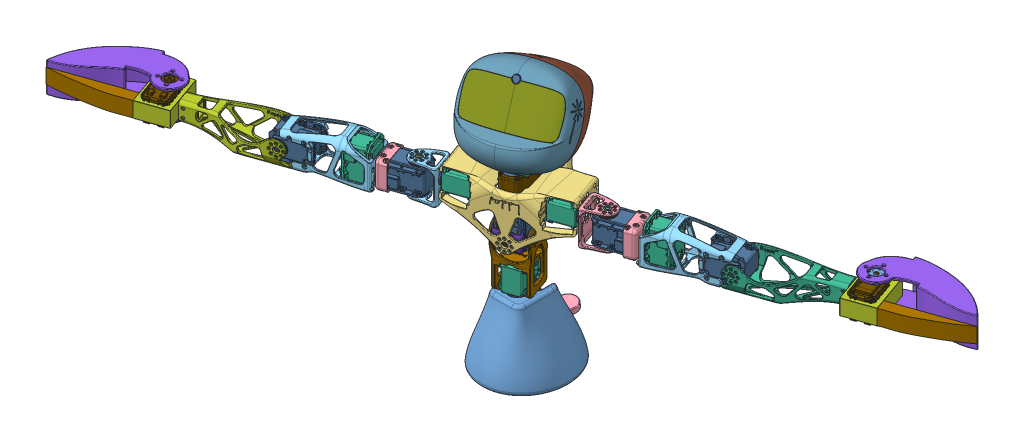
SolidWorks assembly table_support_w_suction_pad, configuration Default. Lengths in mm.
Overall size (1060.3 397.23 515.69).
149 component instances, 45 part files, 8 mates.
Components (placement in the parent):
- support_for_table-1: support_for_table [Défaut] at (0 97 0) size (172.24 95.75 137.34)
- 100LWBN-1: 100LWBN [Default] at (0 0 -15) x (0 0 -1) z (1 0 0) size (122.12 52 100)
  - 100LWBN_suction_pad-1: 100LWBN_suction_pad [Default] at origin size (100 52 100)
  - 100LWBN_shaft-1: 100LWBN_shaft [Default] at (0 35.0737 0) size (7 20 7)
  - 100LWBN_handle-1: 100LWBN_handle [Default] at (0 35.0737 0) x (-0.997983 -0.063481 0) z (0 0 -1) size (75.98 20.58 26)
- Poppy_Humanoid_Torso_Gripper-1: Poppy_Humanoid_Torso_Gripper [Default] at (-5.6475 -20.9875 -16.0345) x (0.943207 0 -0.332206) z (0.332206 0 0.943207) size (1063.51 305.58 172.17)
  - spine-1: spine [Default] at (0 138.4875 17) size (49.29 92.85 54.86)
    - MX-28(T)-2-1: MX-28(T)-2 [Default] x (1 0 0) z (0 -1 0) size (35.6 54.13 45.1)
      - WB_M2.5x8-1: WB_M2.5x8 [Default] at (0 0 25.85) x (0 0 -1) z (-0.991137 0.132843 0) size (10.5 4.5 4.5)
      - dynamixel_x28series(Défaut)-1: dynamixel_x28series(Défaut) [Default] at origin size (35.6 50.71 41.85)
      - trust_washer(Défaut)-1: trust_washer(Défaut) [Default] at (0 0 18.6) x (-0.666375 -0.745617 0) z (0.745617 -0.666375 0) size (22 0.85 22)
      - HN07-N101(Défaut)-1: HN07-N101(Défaut) [Default] at (0 0 18.5) x (1 0 0) z (0 -1 0) size (22 5.85 22)
    - spine-1: spine [Default] at (0 15 0.8) x (-1 0 0) z (0 0 -1) size (49.29 83.95 45.1)
  - double_rotation(full_MX28)-1: double_rotation(full_MX28) [Default] at (0 192.4875 19.8) size (48.5 54.13 85.1)
    - MX-28(U)-6-1: MX-28(U)-6 [Default] x (0 0 1) z (1 0 0) size (35.6 54.13 48.5)
      - dynamixel_x28series(U)-1: dynamixel_x28series(U) [Default] at origin size (35.6 50.71 41.85)
      - trust_washer(U)-1: trust_washer(U) [Default] at (0 0 18.6) x (-0.666375 -0.745617 0) z (0.745617 -0.666375 0) size (22 0.85 22)
      - HN07-N101(U)-1: HN07-N101(U) [Default] at (0 0 18.5) x (1 0 0) z (0 -1 0) size (22 5.85 22)
      - WB_M2.5x8-1: WB_M2.5x8 [Default] at (0 0 25.85) x (0 0 -1) z (-0.991137 0.132843 0) size (10.5 4.5 4.5)
      - WB_M2.5x8-2: WB_M2.5x8 [Default] at (0 0 -22.65) x (0 0 1) z (-0.936501 0.350665 0) size (10.5 4.5 4.5)
      - RX28-CAP-1: RX28-CAP [Default] at (0 0 -20.35) x (-0.995735 -0.092256 0) z (0 0 -1) size (7.2 7.2 1.8)
      - MF106ZZ-1: MF106ZZ [Default] at (0 0 -20.35) x (0.888333 -0.4592 0) z (-0.4592 -0.888333 0) size (11.2 3 11.2)
      - HN07-i101-1: HN07-i101 [Default] at (0 0 -20.5) x (1 0 0) z (0 1 0) size (22 3.05 22)
    - MX-28(T)-3-1: MX-28(T)-3 [Default] at (0 0 -37) x (1 0 0) z (0 0 -1) size (35.6 54.13 45.1)
      - WB_M2.5x8-1: WB_M2.5x8 [Default] at (0 0 25.85) x (0 0 -1) z (-0.991137 0.132843 0) size (10.5 4.5 4.5)
      - dynamixel_x28series(Défaut)-1: dynamixel_x28series(Défaut) [Default] at origin size (35.6 50.71 41.85)
      - trust_washer(Défaut)-1: trust_washer(Défaut) [Default] at (0 0 18.6) x (-0.666375 -0.745617 0) z (0.745617 -0.666375 0) size (22 0.85 22)
      - HN07-N101(Défaut)-1: HN07-N101(Défaut) [Default] at (0 0 18.5) x (1 0 0) z (0 -1 0) size (22 5.85 22)
    - i101_Set(FR07)-1: i101_Set(FR07) [Default] at (0 0 21.6) x (-0.798096 0.60253 0) z (0 0 1) size (22 22 3.8)
      - RX28-CAP-1: RX28-CAP [Default] at (0 0 -0.15) size (7.2 7.2 1.8)
      - MF106ZZ-1: MF106ZZ [Default] at (0 0 -0.15) x (-0.837169 0.546944 0) z (-0.546944 -0.837169 0) size (11.2 3 11.2)
      - HN07-i101-1: HN07-i101 [Default] x (1 0 0) z (0 -1 0) size (22 3.05 22)
    - double_rotation_link(double_MX28)-1: double_rotation_link(double_MX28) [Default] at (0 -0.5 0) size (7.4 26.51 14.1)
    - double_rotation_link(double_MX28)-2: double_rotation_link(double_MX28) [Default] at (0 8.5 0) x (-1 0 0) z (0 0 1) size (7.4 26.51 14.1)
    - i101-Set_to_MX_link(MX28_compatible)-1: i101-Set_to_MX_link(MX28_compatible) [Default] x (0 0 -1) z (1 0 0) size (8.29 28.53 35.81)
  - chest-1: chest [Default] at (7.2825 216.5654 -159.6611) size (167.7 95.79 102.98)
    - AX-12_18A-1: AX-12_18A [Default] at (-7.2825 38.9221 184.4611) x (-1 0 0) z (0 1 0) size (32 50.04 40.32)
      - dynamixel_AXseries-1: dynamixel_AXseries [Default] at origin size (32 50.04 38.37)
      - AX12_horn-1: AX12_horn [Default] at (0 0 19.1) x (0 1 0) z (0 0 1) size (22 22 6.7)
      - BHS_M2_6X8-1: BHS_M2_6X8 [Default] at (0 0 19.55) x (0.628847 -0.777529 0) z (-0.777529 -0.628847 0) size (5.5 9.6 5.5)
    - MX-28(T)-4-1: MX-28(T)-4 [Default] at (-65.2825 25.9221 183.4611) x (0 -1 0) z (-1 0 0) size (35.6 54.13 45.1)
      - WB_M2.5x8-1: WB_M2.5x8 [Default] at (0 0 25.85) x (0 0 -1) z (-0.991137 0.132843 0) size (10.5 4.5 4.5)
      - dynamixel_x28series(Défaut)-1: dynamixel_x28series(Défaut) [Default] at origin size (35.6 50.71 41.85)
      - trust_washer(Défaut)-1: trust_washer(Défaut) [Default] at (0 0 18.6) x (-0.666375 -0.745617 0) z (0.745617 -0.666375 0) size (22 0.85 22)
      - HN07-N101(Défaut)-1: HN07-N101(Défaut) [Default] at (0 0 18.5) x (1 0 0) z (0 -1 0) size (22 5.85 22)
    - MX-28(T)-5-1: MX-28(T)-5 [Default] at (50.7175 25.9221 183.4611) x (0 1 0) z (1 0 0) size (35.6 54.13 45.1)
      - WB_M2.5x8-1: WB_M2.5x8 [Default] at (0 0 25.85) x (0 0 -1) z (-0.991137 0.132843 0) size (10.5 4.5 4.5)
      - dynamixel_x28series(Défaut)-1: dynamixel_x28series(Défaut) [Default] at origin size (35.6 50.71 41.85)
      - trust_washer(Défaut)-1: trust_washer(Défaut) [Default] at (0 0 18.6) x (-0.666375 -0.745617 0) z (0.745617 -0.666375 0) size (22 0.85 22)
      - HN07-N101(Défaut)-1: HN07-N101(Défaut) [Default] at (0 0 18.5) x (1 0 0) z (0 -1 0) size (22 5.85 22)
    - chest-1: chest [Default] at (-7.2825 -24.0779 121.9611) size (157.02 95.79 102.98)
  - shoulder_x-1: shoulder_x [Default] at (119.9166 235.6125 35.5145) x (0 0 -1) z (0 1 0) size (38.6 59.63 48.85)
    - MX-28(U)-7-1: MX-28(U)-7 [Default] at (11.7145 14.4166 -1.625) size (35.6 54.13 48.5)
      - dynamixel_x28series(U)-1: dynamixel_x28series(U) [Default] at origin size (35.6 50.71 41.85)
      - trust_washer(U)-1: trust_washer(U) [Default] at (0 0 18.6) x (-0.666375 -0.745617 0) z (0.745617 -0.666375 0) size (22 0.85 22)
      - HN07-N101(U)-1: HN07-N101(U) [Default] at (0 0 18.5) x (1 0 0) z (0 -1 0) size (22 5.85 22)
      - WB_M2.5x8-1: WB_M2.5x8 [Default] at (0 0 25.85) x (0 0 -1) z (-0.991137 0.132843 0) size (10.5 4.5 4.5)
      - WB_M2.5x8-2: WB_M2.5x8 [Default] at (0 0 -22.65) x (0 0 1) z (-0.936501 0.350665 0) size (10.5 4.5 4.5)
      - RX28-CAP-1: RX28-CAP [Default] at (0 0 -20.35) x (-0.995735 -0.092256 0) z (0 0 -1) size (7.2 7.2 1.8)
      - MF106ZZ-1: MF106ZZ [Default] at (0 0 -20.35) x (0.888333 -0.4592 0) z (-0.4592 -0.888333 0) size (11.2 3 11.2)
      - HN07-i101-1: HN07-i101 [Default] at (0 0 -20.5) x (1 0 0) z (0 1 0) size (22 3.05 22)
    - arm_connector-1: arm_connector [Default] at (11.7145 -28.1834 -11.625) size (38.6 17.77 41.99)
  - upper_arm(double_MX-28)-1: upper_arm(double_MX-28) [Default] at (222.8165 235.6388 -24.353) x (0 0 -1) z (0 1 0) size (49.68 127.28 61.97)
    - MX-28(T)-6-1: MX-28(T)-6 [Default] at (-48.153 54.2165 -11.6513) x (1 0 0) z (0 1 0) size (35.6 54.13 45.1)
      - WB_M2.5x8-1: WB_M2.5x8 [Default] at (0 0 25.85) x (0 0 -1) z (-0.991137 0.132843 0) size (10.5 4.5 4.5)
      - dynamixel_x28series(Défaut)-1: dynamixel_x28series(Défaut) [Default] at origin size (35.6 50.71 41.85)
      - trust_washer(Défaut)-1: trust_washer(Défaut) [Default] at (0 0 18.6) x (-0.666375 -0.745617 0) z (0.745617 -0.666375 0) size (22 0.85 22)
      - HN07-N101(Défaut)-1: HN07-N101(Défaut) [Default] at (0 0 18.5) x (1 0 0) z (0 -1 0) size (22 5.85 22)
    - MX-28(U)-8-1: MX-28(U)-8 [Default] at (-48.153 -31.6835 -1.6513) x (0 0 1) z (1 0 0) size (35.6 54.13 48.5)
      - dynamixel_x28series(U)-1: dynamixel_x28series(U) [Default] at origin size (35.6 50.71 41.85)
      - trust_washer(U)-1: trust_washer(U) [Default] at (0 0 18.6) x (-0.666375 -0.745617 0) z (0.745617 -0.666375 0) size (22 0.85 22)
      - HN07-N101(U)-1: HN07-N101(U) [Default] at (0 0 18.5) x (1 0 0) z (0 -1 0) size (22 5.85 22)
      - WB_M2.5x8-1: WB_M2.5x8 [Default] at (0 0 25.85) x (0 0 -1) z (-0.991137 0.132843 0) size (10.5 4.5 4.5)
      - WB_M2.5x8-2: WB_M2.5x8 [Default] at (0 0 -22.65) x (0 0 1) z (-0.936501 0.350665 0) size (10.5 4.5 4.5)
      - RX28-CAP-1: RX28-CAP [Default] at (0 0 -20.35) x (-0.995735 -0.092256 0) z (0 0 -1) size (7.2 7.2 1.8)
      - MF106ZZ-1: MF106ZZ [Default] at (0 0 -20.35) x (0.888333 -0.4592 0) z (-0.4592 -0.888333 0) size (11.2 3 11.2)
      - HN07-i101-1: HN07-i101 [Default] at (0 0 -20.5) x (1 0 0) z (0 1 0) size (22 3.05 22)
    - upper_arm-1: upper_arm [Default] at (-48.153 -31.6835 -1.6513) size (47.66 107.84 61.97)
  - forearm(left)-1: forearm(left) [Default] at (312.8543 225.3953 -5.788) x (0 0 -1) z (0 1 0) size (55.2 137.66 53.14)
    - forearm(MX28-left)-1: forearm(MX28-left) [Default] at (-29.588 58.3543 8.5922) size (55.2 137.66 53.14)
  - shoulder_x-1-1: shoulder_x-1 [Default] at (-119.9166 235.6125 12.0855) x (0 0 1) z (0 1 0) size (38.6 59.63 48.85)
    - MX-28(U)-9-1: MX-28(U)-9 [Default] at (11.7145 14.4166 -1.625) size (35.6 54.13 48.5)
      - dynamixel_x28series(U)-1: dynamixel_x28series(U) [Default] at origin size (35.6 50.71 41.85)
      - trust_washer(U)-1: trust_washer(U) [Default] at (0 0 18.6) x (-0.666375 -0.745617 0) z (0.745617 -0.666375 0) size (22 0.85 22)
      - HN07-N101(U)-1: HN07-N101(U) [Default] at (0 0 18.5) x (1 0 0) z (0 -1 0) size (22 5.85 22)
      - WB_M2.5x8-1: WB_M2.5x8 [Default] at (0 0 25.85) x (0 0 -1) z (-0.991137 0.132843 0) size (10.5 4.5 4.5)
      - WB_M2.5x8-2: WB_M2.5x8 [Default] at (0 0 -22.65) x (0 0 1) z (-0.936501 0.350665 0) size (10.5 4.5 4.5)
      - RX28-CAP-1: RX28-CAP [Default] at (0 0 -20.35) x (-0.995735 -0.092256 0) z (0 0 -1) size (7.2 7.2 1.8)
      - MF106ZZ-1: MF106ZZ [Default] at (0 0 -20.35) x (0.888333 -0.4592 0) z (-0.4592 -0.888333 0) size (11.2 3 11.2)
      - HN07-i101-1: HN07-i101 [Default] at (0 0 -20.5) x (1 0 0) z (0 1 0) size (22 3.05 22)
    - arm_connector-1: arm_connector [Default] at (11.7145 -28.1834 -11.625) size (38.6 17.77 41.99)
  - upper_arm(double-MX-28_Right)-1: upper_arm(double-MX-28_Right) [Default] at (-222.8165 235.6388 71.953) x (0 0 1) z (0 1 0) size (49.68 127.28 61.97)
    - MX-28(T)-7-1: MX-28(T)-7 [Default] at (-48.153 54.2165 -11.6513) x (1 0 0) z (0 1 0) size (35.6 54.13 45.1)
      - WB_M2.5x8-1: WB_M2.5x8 [Default] at (0 0 25.85) x (0 0 -1) z (-0.991137 0.132843 0) size (10.5 4.5 4.5)
      - dynamixel_x28series(Défaut)-1: dynamixel_x28series(Défaut) [Default] at origin size (35.6 50.71 41.85)
      - trust_washer(Défaut)-1: trust_washer(Défaut) [Default] at (0 0 18.6) x (-0.666375 -0.745617 0) z (0.745617 -0.666375 0) size (22 0.85 22)
      - HN07-N101(Défaut)-1: HN07-N101(Défaut) [Default] at (0 0 18.5) x (1 0 0) z (0 -1 0) size (22 5.85 22)
    - MX-28(U)-10-1: MX-28(U)-10 [Default] at (-48.153 -31.6835 -1.6513) x (0 0 -1) z (-1 0 0) size (35.6 54.13 48.5)
      - dynamixel_x28series(U)-1: dynamixel_x28series(U) [Default] at origin size (35.6 50.71 41.85)
      - trust_washer(U)-1: trust_washer(U) [Default] at (0 0 18.6) x (-0.666375 -0.745617 0) z (0.745617 -0.666375 0) size (22 0.85 22)
      - HN07-N101(U)-1: HN07-N101(U) [Default] at (0 0 18.5) x (1 0 0) z (0 -1 0) size (22 5.85 22)
      - WB_M2.5x8-1: WB_M2.5x8 [Default] at (0 0 -22.65) x (0 0 1) z (-0.936501 0.350665 0) size (10.5 4.5 4.5)
      - WB_M2.5x8-2: WB_M2.5x8 [Default] at (0 0 25.85) x (0 0 -1) z (-0.991137 0.132843 0) size (10.5 4.5 4.5)
      - RX28-CAP-1: RX28-CAP [Default] at (0 0 -20.35) x (-0.995735 -0.092256 0) z (0 0 -1) size (7.2 7.2 1.8)
      - MF106ZZ-1: MF106ZZ [Default] at (0 0 -20.35) x (0.888333 -0.4592 0) z (-0.4592 -0.888333 0) size (11.2 3 11.2)
      - HN07-i101-1: HN07-i101 [Default] at (0 0 -20.5) x (1 0 0) z (0 1 0) size (22 3.05 22)
    - upper_arm-1: upper_arm [Default] at (-48.153 -31.6835 -1.6513) size (47.66 107.84 61.97)
  - forearm(right)-1: forearm(right) [Default] at (-312.8543 225.3953 53.388) x (0 0 1) z (0 1 0) size (55.2 137.66 53.14)
    - forearm(MX-28-right)-1: forearm(MX-28-right) [Default] at (-29.588 58.3543 8.5922) size (55.2 137.66 53.14)
  - head-1: head [Default] at (0 296.4875 24.8) x (1 0 0) z (0 0.34202 0.939693) size (152.35 129.81 135.97)
    - AX-12_18A-1-1: AX-12_18A-1 [Default] x (0 0.939693 0.34202) z (1 0 0) size (32 50.04 40.32)
      - dynamixel_AXseries-1: dynamixel_AXseries [Default] at origin size (32 50.04 38.37)
      - AX12_horn-1: AX12_horn [Default] at (0 0 19.1) x (0 1 0) z (0 0 1) size (22 22 6.7)
      - BHS_M2_6X8-1: BHS_M2_6X8 [Default] at (0 0 19.55) x (0.628847 -0.777529 0) z (-0.777529 -0.628847 0) size (5.5 9.6 5.5)
    - Videw_JDEPC-OV04(170_FOV_lens)-1: Videw_JDEPC-OV04(170_FOV_lens) [Default] at (0 79.5531 9.1743) x (1 0 0) z (0 0.162719 0.986672) size (60.45 10 12.9)
      - Videw_JDEPC-OV04-1: Videw_JDEPC-OV04 [Default] at origin size (60 8 0.6)
      - SM05B-SRSS-TB-1: SM05B-SRSS-TB [Default] at (-23.7 0 0.6) x (0 -1 0) z (-1 0 0) size (7 2.9 4.95)
      - 170_FOV_lens-1: 170_FOV_lens [Default] at (0 0 0.6) size (10 10 12.3)
    - head_back-1: head_back [Default] at origin size (139.97 128.52 115.71)
    - Odroid_U3-1: Odroid_U3 [Default] at (41.5 40.9083 -63.8082) x (1 0 0) z (0 -0.087156 -0.996195) size (83 21.55 48.75)
    - fake_manga_screen-1: fake_manga_screen [Default] at (0 46.1109 21.48) x (1 0 0) z (0 0.162719 0.986672) size (106 70.75 3.7)
    - head_face-1: head_face [Default] at origin size (137.8 118.1 101.78)
    - screen_support-1: screen_support [Default] at origin size (119.01 63.24 19.97)
    - screen-1: screen [Default] at origin size (152.35 100.2 22.24)
    - camera_support-1: camera_support [Default] at (0 0.0163 0.0987) size (81.74 18.94 5.38)
    - VisatonK20.40_speaker-1: VisatonK20.40_speaker [Default] at (-59.643 48.4618 4.5746) x (-0.088219 -0.989732 0.112468) z (-0.984948 0.103522 0.138425) size (40 20 7.34)
    - VisatonK20.40_speaker-2: VisatonK20.40_speaker [Default] at (59.643 48.4618 4.5746) x (0.088219 -0.989732 0.112468) z (0.984948 0.103522 0.138425) size (40 20 7.34)
    - speaker_left-1: speaker_left [Default] at origin size (22.34 61.46 49.54)
    - speaker_right-1: speaker_right [Default] at origin size (22.34 61.46 49.54)
    - 9DOF-Razor-v23-1: 9DOF-Razor-v23 [Default] at (0 23.915 -2) size (41 7.1 28)
  - shoulder(MX-28_Left)-1: shoulder(MX-28_Left) [Default] at (51.5 233.9875 23.8) x (1 0 0) z (0 1 0) size (41.1 39.63 50.34)
  - shoulder(MX-28_Right)-1: shoulder(MX-28_Right) [Default] at (-105.5 233.9875 23.8) x (1 0 0) z (0 1 0) size (41.1 39.63 50.34)
  - neck-1: neck [Default] at (0 296.4875 24.8) size (48.14 31.5 23.18)
  - Gripper_assembled-1: Gripper_assembled [Default] at (372.0424 195.988 42.2134) x (1 0 0) z (0 1 0) size (177.25 101.63 61.68)
    - AX-12_18A-1-1: AX-12_18A-1 [Default] at (23.4576 40.9134 34.0008) size (32 50.04 40.32)
      - dynamixel_AXseries-1: dynamixel_AXseries [Default] at origin size (32 50.04 38.37)
      - AX12_horn-1: AX12_horn [Default] at (0 0 19.1) x (0 1 0) z (0 0 1) size (22 22 6.7)
      - BHS_M2_6X8-1: BHS_M2_6X8 [Default] at (0 0 19.55) x (0.628847 -0.777529 0) z (-0.777529 -0.628847 0) size (5.5 9.6 5.5)
    - Gripper-1: Gripper [Default] at (-1.4424 28.9134 34.0008) x (1 0 0) z (0 -1 0) size (62 22 60)
    - Gripper Top claw-1: Gripper Top claw [Default] at (23.4576 40.9134 18.0408) x (0 0 1) z (-0.982321 0.187207 0) size (61.68 75.14 148.57)
    - Gripper bottom claw fixed-1: Gripper bottom claw fixed [Default] at (44.4576 14.1634 44.7508) size (104.6 15.83 21.5)
  - Gripper_assembled-2: Gripper_assembled [Default] at (-372.0424 266.4896 42.2134) x (-1 0 0) z (0 -1 0) size (177.25 101.63 61.68)
    - AX-12_18A-1-1: AX-12_18A-1 [Default] at (23.4576 40.9134 34.0008) size (32 50.04 40.32)
      - dynamixel_AXseries-1: dynamixel_AXseries [Default] at origin size (32 50.04 38.37)
      - AX12_horn-1: AX12_horn [Default] at (0 0 19.1) x (0 1 0) z (0 0 1) size (22 22 6.7)
      - BHS_M2_6X8-1: BHS_M2_6X8 [Default] at (0 0 19.55) x (0.628847 -0.777529 0) z (-0.777529 -0.628847 0) size (5.5 9.6 5.5)
    - Gripper-1: Gripper [Default] at (-1.4424 28.9134 34.0008) x (1 0 0) z (0 -1 0) size (62 22 60)
    - Gripper Top claw-1: Gripper Top claw [Default] at (23.4576 40.9134 18.0408) x (0 0 1) z (-0.982321 0.187207 0) size (61.68 75.14 148.57)
    - Gripper bottom claw fixed-1: Gripper bottom claw fixed [Default] at (44.4576 14.1634 44.7508) size (104.6 15.83 21.5)
Mates (geometry in assembly coordinates):
- Coincident1: coincident aligned: plane of support_for_table-1 through (0 0 0) normal (0 1 0); plane of 100LWBN-1/100LWBN_suction_pad-1
- Coincident2: coincident aligned: plane of support_for_table-1 through (0 97 0) normal (1 0 0); plane of 100LWBN-1/100LWBN_suction_pad-1 through (0 0 -15) normal (1 0 0)
- Coincident4: coincident anti-aligned: plane of support_for_table-1 through (0 -12 1) normal (0 0 -1); plane of 100LWBN-1/100LWBN_suction_pad-1 through (-15 52 1) normal (0 0 1)
- Coincident5: coincident aligned: plane of support_for_table-1 through (0 97 0) normal (0 0 1); plane of assembly through (0 0 0) normal (0 0 1)
- Coincident6: coincident aligned: plane of support_for_table-1 through (0 0 0) normal (0 1 0); plane of assembly through (0 0 0) normal (0 1 0)
- Coincident7: coincident aligned: plane of support_for_table-1 through (0 97 0) normal (1 0 0); plane of assembly through (0 0 0) normal (1 0 0)
- Concentric1: concentric anti-aligned: cylinder of support_for_table-1 through (0 97.3024 0) axis (0 -1 0) radius 4.3; cylinder of Poppy_Humanoid_Torso_Gripper-1/spine-1/MX-28(T)-2-1/HN07-N101(Défaut)-1 through (0 93.8575 0) axis (0 1 0) radius 4
- Coincident8: coincident anti-aligned: plane of support_for_table-1 through (-13.5 97 -30) normal (0 1 0); plane of Poppy_Humanoid_Torso_Gripper-1/spine-1/MX-28(T)-2-1/HN07-N101(Défaut)-1 through (0 97 0) normal (0 -1 0)
